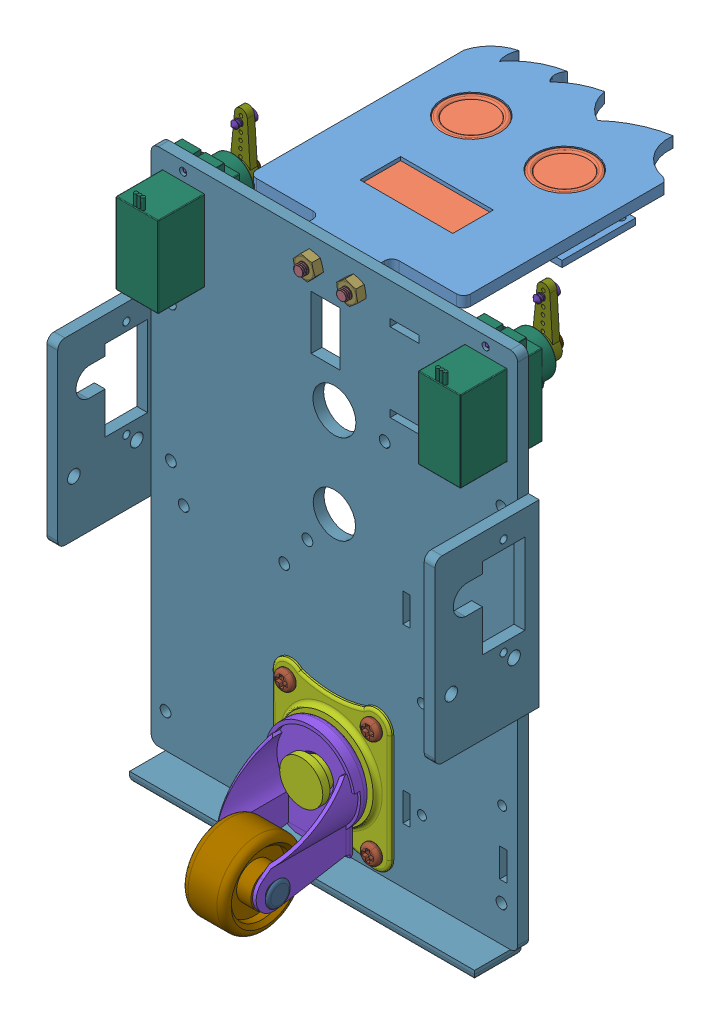
SolidWorks assembly DYOR_3D_OL_PU, configuration Predeterminado. Lengths in mm.
Overall size (108 155.56 112.97).
66 component instances, 23 part files, 15 mates.
Components (placement in the parent):
- HC-SR04 Ping Sensor-1: HC-SR04 Ping Sensor [Default] at (9.5272 28.7888 -38.4611) x (0 0 -1) z (0 1 0) size (25.18 45 18.07)
  - PCB-1: PCB [Default] at origin size (20.5 45 1.75)
  - Transducer-1: Transducer [Default] at (0 -13 13.25) x (1 0 0) z (0 -1 0) size (15.88 12 15.88)
  - Transducer-2: Transducer [Default] at (0 13 13.25) x (1 0 0) z (0 -1 0) size (15.88 12 15.88)
  - 3 Pin Header 90 Degree-1: 3 Pin Header 90 Degree [Default] at (8.4275 0 -1.25) x (-1 0 0) z (0 -1 0) size (8 7.82 10)
  - 14 Pin SMT-1: 14 Pin SMT [Default] at (-0.35 -18.5 -0.85) x (0 -1 0) z (1 0 0) size (6 1.6 8.8)
  - 14 Pin SMT-2: 14 Pin SMT [Default] at (0 -0.3826 -0.85) x (1 0 0) z (0 1 0) size (6 1.6 8.8)
  - 14 Pin SMT-3: 14 Pin SMT [Default] at (0 17.5274 -0.85) x (1 0 0) z (0 1 0) size (6 1.6 8.8)
  - Cap1 SMT-1: Cap1 SMT [Default] at (-1.755 7.4774 -0.9689) x (0 1 0) z (-1 0 0) size (4.5 1.84 1.75)
  - Cap1 SMT-2: Cap1 SMT [Default] at (6.835 7.4774 -0.9689) x (0 1 0) z (-1 0 0) size (4.5 1.84 1.75)
  - Cap1 SMT-3: Cap1 SMT [Default] at (-6.835 7.4774 -0.9689) x (0 1 0) z (-1 0 0) size (4.5 1.84 1.75)
  - Cap1 SMT-4: Cap1 SMT [Default] at (4.295 7.4774 -0.9689) x (0 1 0) z (-1 0 0) size (4.5 1.84 1.75)
  - Cap1 SMT-5: Cap1 SMT [Default] at (1.755 7.4774 -0.9689) x (0 1 0) z (-1 0 0) size (4.5 1.84 1.75)
  - Cap1 SMT-6: Cap1 SMT [Default] at (-4.295 7.4774 -0.9689) x (0 1 0) z (-1 0 0) size (4.5 1.84 1.75)
  - HC-SR04 Crystal-1: HC-SR04 Crystal [Default] at (-8.3 0 1.75) x (0 -1 0) z (0 0 1) size (10 3.5 2.7)
- CA-1: CA [Predeterminado] at (-2.2402 -1.1323 0) x (1 0.000939 0) z (0 0 1) size (33 45.94 43.2)
  - Caster Wheel-1: Caster Wheel [Default] at (57.6387 -78.841 57.7572) x (0 1 0) z (-1 0 0) size (45.94 37.59 33)
    - caster holder-1: caster holder [Default] at (-24.0751 44.7184 29.5137) x (1 0 0) z (0 0 -1) size (39 9.27 33)
    - holder-1: holder [Default] at (-1.5751 42.9484 46.0137) x (0 0 1) z (1 0 0) size (25 28.07 31.31)
    - caster wheel-1: caster wheel [Default] at (-15.6961 19.9484 46.0137) x (0.997275 0.073773 0) z (0 0 1) size (23 23 14)
    - Part4-1: Part4 [Default] at (-15.6961 19.9484 55.0137) x (-0.978448 0.206495 0) z (0 0 -1) size (7 7 20)
  - M3x6 Philips Screw-1: M3x6 Philips Screw [Predeterminado] at (23.625 -65.4161 13.5389) size (5.3 5.3 7.81)
  - M3x6 Philips Screw-2: M3x6 Philips Screw [Predeterminado] at (-0.375 -65.4161 13.5389) size (5.3 5.3 7.81)
  - M3x6 Philips Screw-3: M3x6 Philips Screw [Predeterminado] at (-0.375 -95.4161 13.5389) size (5.3 5.3 7.81)
  - M3x6 Philips Screw-4: M3x6 Philips Screw [Predeterminado] at (23.625 -95.4161 13.5389) size (5.3 5.3 7.81)
  - M3 Nut-1: M3 Nut [Predeterminado] at (23.625 -65.4161 11.0389) size (6.27 6.27 2.71)
  - M3 Nut-2: M3 Nut [Predeterminado] at (-0.375 -65.4161 11.0389) size (6.27 6.27 2.71)
  - M3 Nut-3: M3 Nut [Predeterminado] at (-0.375 -95.4161 11.0389) size (6.27 6.27 2.71)
  - M3 Nut-4: M3 Nut [Predeterminado] at (23.625 -95.4161 11.0389) size (6.27 6.27 2.71)
- M3x10 Philips Screw-2: M3x10 Philips Screw [Predeterminado] at (3.418 36.0388 6.5389) x (0.88719 -0.461404 0) z (0 0 -1) size (5.3 5.3 11.8)
- M3x10 Philips Screw-3: M3x10 Philips Screw [Predeterminado] at (15.418 36.0388 6.5389) x (0.471193 -0.88203 0) z (0 0 -1) size (5.3 5.3 11.8)
- M3 Nut-1: M3 Nut [Predeterminado] at (3.418 36.0388 16.5389) x (0.222076 0.975029 0) z (0 0 1) size (6.27 6.27 2.71)
- M3 Nut-2: M3 Nut [Predeterminado] at (15.418 36.0388 11.0389) x (-0.334718 -0.942319 0) z (0 0 -1) size (6.27 6.27 2.71)
- BasePU-1: BasePU [Predeterminado] at (-51.2528 96.5598 9.5389) size (108 147.56 29)
- PU-1: PU [Predeterminado] at (-155.9776 204.2742 -130.283) size (95.94 37.23 33.31)
  - sg90-1: sg90 [Default] at (201.5956 -166.7354 155.7219) x (0 -1 0) z (1 0 0) size (31.9 29.9 11.8)
  - sg90-2: sg90 [Default] at (117.452 -166.7354 155.7219) x (0 -1 0) z (1 0 0) size (31.9 29.9 11.8)
  - SG90 plastic Horn-1: SG90 plastic Horn [Default] at (123.352 -172.6354 127.0219) x (0.017141 0.999853 0) z (-0.999853 0.017141 0) size (19.4 4 7.07)
  - SG90 plastic Horn-2: SG90 plastic Horn [Default] at (207.4956 -172.6354 127.0219) x (0.020276 0.999794 0) z (-0.999794 0.020276 0) size (19.4 4 7.07)
  - M2x6 SelfTap Screw-1: M2x6 SelfTap Screw [Predeterminado] at (207.4956 -164.3354 136.8219) x (-0.923728 -0.383049 0) z (0 0 -1) size (3.4 3.28 6)
  - M2x6 SelfTap Screw-2: M2x6 SelfTap Screw [Predeterminado] at (207.4956 -191.6354 136.3219) x (-0.923728 -0.383049 0) z (0 0 -1) size (3.4 3.28 6)
  - M2x6 SelfTap Screw-3: M2x6 SelfTap Screw [Predeterminado] at (123.352 -164.3354 136.8219) x (-0.993348 0.115149 0) z (0 0 -1) size (3.4 3.28 6)
  - M2x6 SelfTap Screw-4: M2x6 SelfTap Screw [Predeterminado] at (123.352 -191.6354 136.8219) x (-0.923728 -0.383049 0) z (0 0 -1) size (3.4 3.28 6)
  - (M2_3_mm)_90116A007_METRIC 316 SS PAN HEAD PHILLIPS MACHINE SCREW-1: (M2_3_mm)_90116A007_METRIC 316 SS PAN HEAD PHILLIPS MACHINE SCREW [90116A007] at (123.352 -172.6354 127.0219) x (-0.923728 -0.383049 0) z (0 0 -1) size (4 4 4.68)
  - (M2_3_mm)_90116A007_METRIC 316 SS PAN HEAD PHILLIPS MACHINE SCREW-2: (M2_3_mm)_90116A007_METRIC 316 SS PAN HEAD PHILLIPS MACHINE SCREW [90116A007] at (207.4956 -172.6354 127.0219) x (-0.923728 -0.383049 0) z (0 0 -1) size (4 4 4.68)
  - M2x6 SelfTap Screw-5: M2x6 SelfTap Screw [Predeterminado] at (123.352 -160.1354 123.5219) x (-0.923728 -0.383049 0) z (0 0 -1) size (3.4 3.28 6)
  - M2x6 SelfTap Screw-6: M2x6 SelfTap Screw [Predeterminado] at (207.4956 -160.1354 123.5219) x (-0.923728 -0.383049 0) z (0 0 -1) size (3.4 3.28 6)
- Front_OL-1: Front_OL [Predeterminado] at (-51.1718 39.5388 -46.4821) x (1 0 0) z (0 1 0) size (59.69 72.38 11)
- OLED_0.91_128x32-1: OLED_0.91_128x32 [Predeterminado] at (10.618 39.0288 -13.1552) x (1 0 0) z (0 1 0) size (38.3 12.1 11.46)
  - OLED_0.91_128x32.stp-1: OLED_0.91_128x32.stp [Predeterminado] at origin size (38.3 12.1 11.46)
    - OLED_0.91_128x32.stp-1: OLED_0.91_128x32.stp [Predeterminado] at origin size (38.3 12.1 2.57)
    - Pin Header 4 x 1 TH 2.54mm Pitch.stp-1: Pin Header 4 x 1 TH 2.54mm Pitch.stp [Predeterminado] at (-17.55 -3.81 -2.6) size (2.54 10.16 11.43)
    - RESC-0603.stp-1: RESC-0603.stp [Predeterminado] at (4.3 -5.3 0) x (1 0 0) z (0 0 -1) size (1.7 0.9 0.55)
    - RESC-0603.stp-2: RESC-0603.stp [Predeterminado] at (4.3 -3.8 0) x (1 0 0) z (0 0 -1) size (1.7 0.9 0.55)
    - RESC-0603.stp-3: RESC-0603.stp [Predeterminado] at (4.3 -2.3 0) x (1 0 0) z (0 0 -1) size (1.7 0.9 0.55)
    - RESC-0603.stp-4: RESC-0603.stp [Predeterminado] at (4.3 -0.8 0) x (1 0 0) z (0 0 -1) size (1.7 0.9 0.55)
    - RESC-0603.stp-5: RESC-0603.stp [Predeterminado] at (4.3 0.7 0) x (1 0 0) z (0 0 -1) size (1.7 0.9 0.55)
    - RESC-0603.stp-6: RESC-0603.stp [Predeterminado] at (4.3 2.2 0) x (1 0 0) z (0 0 -1) size (1.7 0.9 0.55)
    - RESC-0603.stp-7: RESC-0603.stp [Predeterminado] at (4.3 3.7 0) x (1 0 0) z (0 0 -1) size (1.7 0.9 0.55)
    - RESC-0603.stp-8: RESC-0603.stp [Predeterminado] at (4.3 5.2 0) x (1 0 0) z (0 0 -1) size (1.7 0.9 0.55)
    - RESC-0603.stp-9: RESC-0603.stp [Predeterminado] at (-1.4 -3.06 0) x (1 0 0) z (0 0 -1) size (1.7 0.9 0.55)
    - RESC-0603.stp-10: RESC-0603.stp [Predeterminado] at (-1.4 -1.56 0) x (1 0 0) z (0 0 -1) size (1.7 0.9 0.55)
    - RESC-0603.stp-11: RESC-0603.stp [Predeterminado] at (-1.4 -0.06 0) x (1 0 0) z (0 0 -1) size (1.7 0.9 0.55)
    - RESC-0603.stp-12: RESC-0603.stp [Predeterminado] at (-1.4 1.44 0) x (1 0 0) z (0 0 -1) size (1.7 0.9 0.55)
    - RESC-0603.stp-13: RESC-0603.stp [Predeterminado] at (-1.4 2.94 0) x (1 0 0) z (0 0 -1) size (1.7 0.9 0.55)
    - 2SD0601A.stp-1: 2SD0601A.stp [Predeterminado] at (-9.8 -1.3 -0.08) x (1 0 0) z (0 1 0) size (2.76 1.18 2.9)
Mates (geometry in assembly coordinates):
- Concéntrica15: concentric: circle of M3 Nut-2; circle of BasePU-1
- Coincidente15: coincident: plane of M3 Nut-1 through (3.418 36.0388 12.5389) normal (0 0 -1); plane of BasePU-1 through (58.418 40.5388 12.5389) normal (0 0 1)
- Coincidente16: coincident: plane of M3 Nut-2 through (15.418 36.0388 12.5389) normal (0 0 -1); plane of BasePU-1 through (58.418 40.5388 12.5389) normal (0 0 1)
- Coincidente17: coincident: plane of BasePU-1 through (57.418 37.5388 12.5389) normal (0 -1 0); plane of PU-1/sg90-1 through (57.418 37.5388 25.4389) normal (0 1 0)
- Coincidente18: coincident: plane of BasePU-1 through (58.418 40.5388 9.5389) normal (0 0 -1); plane of PU-1/sg90-1 through (57.418 10.3388 9.5389) normal (0 0 1)
- Concéntrica16: concentric: circle of BasePU-1; circle of PU-1/M2x6 SelfTap Screw-2
- Coincidente19: coincident: plane of BasePU-1 through (58.418 40.5388 9.5389) normal (0 0 -1); plane of Front_OL-1 through (-0.582 42.5388 9.5389) normal (0 0 1)
- Concéntrica17: concentric: circle of BasePU-1; circle of Front_OL-1
- Paralelo1: parallel: plane of BasePU-1 through (-7.6975 42.5388 12.5389) normal (0 1 0); plane of Front_OL-1 through (-2.582 42.5388 8.5389) normal (0 1 0)
- Concéntrica18: concentric: circle of HC-SR04 Ping Sensor-1/Transducer-1; circle of Front_OL-1
- Concéntrica19: concentric: circle of HC-SR04 Ping Sensor-1/Transducer-2; circle of Front_OL-1
- Coincidente21: coincident: plane of HC-SR04 Ping Sensor-1/Transducer-1 through (22.5272 42.5388 -46.4011) normal (0 1 0); plane of Front_OL-1 through (-2.582 42.5388 8.5389) normal (0 1 0)
- Coincidente22: coincident: plane of Front_OL-1 through (-8.532 40.5388 -7.1052) normal (0 0 -1); plane of ? through (-26.5025 39.0288 -7.1052) normal (0 0 1)
- Distancia1: distance = 1 mm: plane of OLED_0.91_128x32-1/OLED_0.91_128x32.stp-1/OLED_0.91_128x32.stp-1 through (9.418 41.5388 -13.1552) normal (0 1 0); plane of Front_OL-1 through (-2.582 42.5388 8.5389) normal (0 1 0)
- Coincidente24: coincident: plane of Front_OL-1 through (29.768 40.5388 -7.1052) normal (-1 0 0); plane of OLED_0.91_128x32-1/OLED_0.91_128x32.stp-1/OLED_0.91_128x32.stp-1 through (29.768 39.0288 -7.1052) normal (1 0 0)
